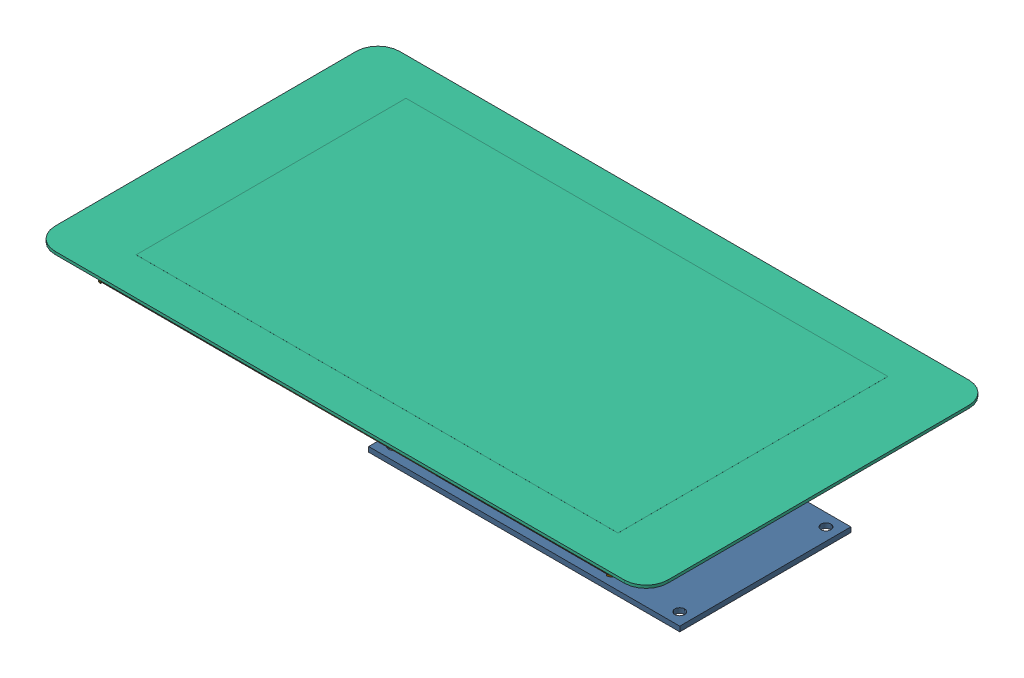
SolidWorks assembly Raspberry Pi Display V1.1, configuration Défaut. Lengths in mm.
Overall size (197 17.2 110.76).
21 component instances, 11 part files, 0 mates.
Components (placement in the parent):
- Raspberry Pi Display V1.1.STEP-1: Raspberry Pi Display V1.1.STEP [Défaut] at origin size (203.95 17.2 110.76)
  - 61300511121 (rev1).STEP-1: 61300511121 (rev1).STEP [Défaut] at (20.4766 -31.4206 253.3295) x (1 0 0) z (0 0.999997 0.002523) size (12.7 11.54 2.54)
    - 6130xx11121_PIN.STEP-1: 6130xx11121_PIN.STEP [Défaut] at (-5.08 1.5 0) x (1 0 0) z (0 -1 0) size (0.64 0.64 11.54)
    - 6130xx11121_PIN.STEP-2: 6130xx11121_PIN.STEP [Défaut] at (-2.54 1.5 0) x (1 0 0) z (0 -1 0) size (0.64 0.64 11.54)
    - 6130xx11121_PIN.STEP-3: 6130xx11121_PIN.STEP [Défaut] at (0 1.5 0) x (1 0 0) z (0 -1 0) size (0.64 0.64 11.54)
    - 6130xx11121_PIN.STEP-4: 6130xx11121_PIN.STEP [Défaut] at (2.54 1.5 0) x (1 0 0) z (0 -1 0) size (0.64 0.64 11.54)
    - 6130xx11121_PIN.STEP-5: 6130xx11121_PIN.STEP [Défaut] at (5.08 1.5 0) x (1 0 0) z (0 -1 0) size (0.64 0.64 11.54)
    - 61300511121.STEP-1: 61300511121.STEP [Défaut] at origin size (12.7 2.54 2.54)
  - 61400416021_Download_STP_61400416021_rev1.STEP-1: 61400416021_Download_STP_61400416021_rev1.STEP [Défaut] at (-25.1734 -34.2046 286.5886) x (0 -0.002523 0.999997) z (0 0.999997 0.002523) size (16.2 14 11.7)
    - 61400416021_Insulator.STEP-1: 61400416021_Insulator.STEP [Défaut] at (0 4.375 0.44) size (13.25 13.55 6.54)
    - 61400416021_Contact Plating.STEP-1: 61400416021_Contact Plating.STEP [Défaut] at (-3.5 4.65 0.29) size (1.2 12.2 8.19)
    - 61400416021_Contact Plating.STEP-2: 61400416021_Contact Plating.STEP [Défaut] at (-1 4.65 0.29) size (1.2 12.2 8.19)
    - 61400416021_Contact Plating.STEP-3: 61400416021_Contact Plating.STEP [Défaut] at (3.5 4.65 0.29) size (1.2 12.2 8.19)
    - 61400416021_Contact Plating.STEP-4: 61400416021_Contact Plating.STEP [Défaut] at (1 4.65 0.29) size (1.2 12.2 8.19)
    - 61400416021_Shielding.STEP-1: 61400416021_Shielding.STEP [Défaut] at (0.025 0.2 -0.07) x (-1 0 0) z (0 0 -1) size (16.2 14 11.7)
  - FAV.STEP-1: FAV.STEP [Défaut] at (-3.6734 -21.7079 276.0341) x (1 0 0) z (0 -0.002523 0.999997) size (197 1.01 110.76)
  - Verre.STEP-1: Verre.STEP [Défaut] at (-8.7234 -22.3082 276.1526) x (1 0 0) z (0 -0.002523 0.999997) size (177 0.6 97)
  - Dalle.STEP-1: Dalle.STEP [Défaut] at (-2.4734 -25.6113 277.3693) x (1 0 0) z (0 -0.002523 0.999997) size (164.5 3.3 98.75)
  - Carter dalle.STEP-1: Carter dalle.STEP [Défaut] at (-2.8234 -25.1118 277.5755) x (-1 0 0) z (0 -0.002523 0.999997) size (166.2 6 100.6)
  - PCB.STEP-1: PCB.STEP [Défaut] at (1.7766 -28.5992 272.5667) x (1 0 0) z (0 0.002523 -0.999997) size (100 1.6 55) (hidden)
  - 629105150521 (rev1).STEP-1: 629105150521 (rev1).STEP [Défaut] at (23.5522 -31.3088 296.21) x (-1 0 0) z (0 -0.999997 -0.002523) size (8 6.6 4.53)
